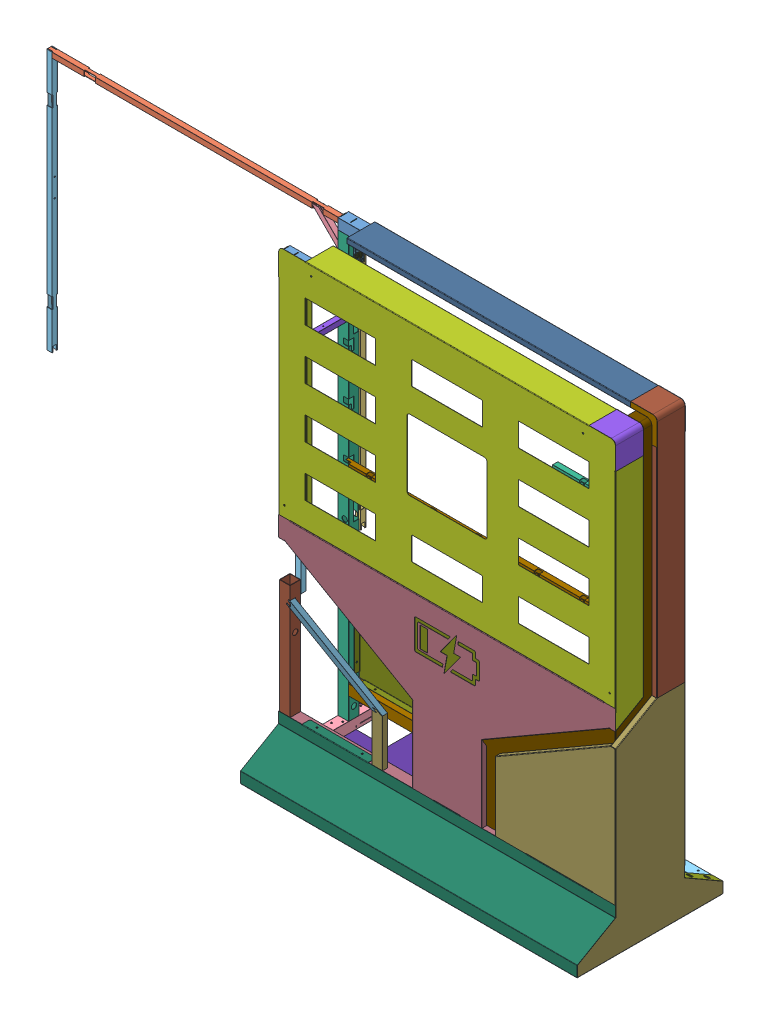
SolidWorks assembly StandV2, configuration Default. Lengths in mm.
Overall size (2398.62 1730.34 547.63).
95 component instances, 56 part files, 48 mates.
Components (placement in the parent):
- Chassis^StandV2-1: Chassis^StandV2 [Default] at (0 0 963.5395) size (2397 1715.34 546.5) (virtual)
  - caster wheel.step-1: caster wheel.step [Default] at (-58.45 -50.6 58.45) x (0 0 1) z (-1 0 0) size (94.94 69.87 60)
  - wheel mount-1: wheel mount [Default] at (5 1.5 -5) x (0 0 1) z (0 -1 0) size (125 125 2)
  - side wheel support-1: side wheel support [Default] at (-104 -13.5 2) size (116.65 17 2)
  - side wheel support-2: side wheel support [Default] at (0 -13.5 104) x (0 0 -1) z (1 0 0) size (116.65 17 2)
  - Bottom depth-1: Bottom depth [Default] at (1065 -10.5 -391.5) size (40 40 546.5)
  - Bottom width-1: Bottom width [Default] at (1085 -10.5 -391.5) x (-1 0 0) z (0 0 -1) size (1220 40 40)
  - Bottom width-2: Bottom width [Default] at (-135 -10.5 155) size (1220 40 40)
  - Bottom depth-2: Bottom depth [Default] at (-115 -10.5 155) x (-1 0 0) z (0 0 -1) size (40 40 546.5)
  - Height main hinge-1: Height main hinge [Default] at (-155 1647 -208.2) x (0 0 -1) z (-1 0 0) size (40 1637.5 40)
  - Skewed depth-1: Skewed depth [Default] at (-115 -5.141 135) x (-1 0 0) z (0 0.5 -0.866025) size (40 40 165.35)
  - Skewed depth-2: Skewed depth [Default] at (1065 -5.141 -371.5) x (1 0 0) z (0 0.5 0.866025) size (40 40 165.35)
  - Skewed depth right-1: Skewed depth right [Default] at (1105 -5.141 135) x (-1 0 0) z (0 0.5 -0.866025) size (40 40 165.35)
  - Skewed depth right-2: Skewed depth right [Default] at (-155 -5.141 -371.5) x (1 0 0) z (0 0.5 0.866025) size (40 40 165.35)
  - Width main thick bottom-1: Width main thick bottom [Default] at (1085 152 -208.2) x (0 0 -1) z (0 1 0) size (40 1220 40)
  - Height main lock-1: Height main lock [Default] at (1105 1647 -208.2) x (-1 0 0) z (0 0 1) size (40 1637.5 40)
  - Height main thick front bottom-1: Height main thick front bottom [Default] at (-155 580.5 -28.1973) x (1 0 0) z (0 0 -1) size (40 571 40)
  - bottom center down height-1: bottom center down height [Default] at (191.4 132 -8.1973) x (0 0 1) z (-1 0 0) size (20 208 40)
  - Width main thick bottom front-1: Width main thick bottom front [Default] at (1085 112 -28.1973) x (0 0 1) z (0 -1 0) size (40 1220 40)
  - bottom Skewed1-1: bottom Skewed1 [Default] at (231.4 330 -8.1973) x (-0.5 -0.866025 0) z (0 0 -1) size (20 405 20)
  - bottom center height-1: bottom center height [Default] at (381.93 132 -8.1973) x (0 0 1) z (-1 0 0) size (20 334 40)
  - bottom skewed2-1: bottom skewed2 [Default] at (409.1926 450.2776 11.8027) x (0.5 0.866025 0) z (0 0 1) size (20 623 20)
  - center front-1: center front [Default] at (1053.1943 767.7776 -8.1973) x (0 -1 0) z (0 0 -1) size (20 1156.4 20)
  - height main thick front top-1: height main thick front top [Default] at (-155 748 11.8027) size (40 899 40)
  - width main thick-1: width main thick [Default] at (1105 1606 -28.1973) x (0 0 1) z (0 -1 0) size (40 1260 40)
  - bottom center height right-1: bottom center height right [Default] at (528.06 132 -8.1973) x (0 0 1) z (-1 0 0) size (20 334 40)
  - bottom skewed2-2: bottom skewed2 [Default] at (540.7974 450.2776 -8.1973) x (-0.5 0.866025 0) z (0 0 -1) size (20 623 20)
  - height main thick front topR-1: height main thick front topR [Default] at (1065 748 11.8027) size (40 899 40)
  - bottom center down heightR-1: bottom center down heightR [Default] at (758.6 132 11.8027) x (0 0 -1) z (1 0 0) size (20 208 40)
  - bottom Skewed1-2: bottom Skewed1 [Default] at (718.6 330 11.8027) x (0.5 -0.866025 0) z (0 0 1) size (20 405 20)
  - midJoint-1: midJoint [Default] at (-114 534.25 -48.1973) x (-1 0 0) z (0 0 -1) size (20 260 20)
  - midJoint-2: midJoint [Default] at (1064 794.25 -48.1973) x (1 0 0) z (0 0 -1) size (20 260 20)
  - width sub-1: width sub [Default] at (1085 1416 -8.1973) x (0 0 1) z (0 -1 0) size (20 1220 20)
  - Height main thick front bottomR-1: Height main thick front bottomR [Default] at (1065 580.5 -28.1973) x (1 0 0) z (0 0 -1) size (40 571 40)
  - width main thick-2: width main thick [Default] at (1105 1606 -248.2) x (0 0 1) z (0 -1 0) size (40 1260 40)
  - shelf depth-1: shelf depth [Default] at (-50 1416 6.8) x (0 1 0) z (-1 0 0) size (20 230 20)
  - width subR-1: width subR [Default] at (-135 1416 -208.2) x (0 0 -1) z (0 -1 0) size (20 1220 20)
  - height sub-1: height sub [Default] at (285 826 -8.1973) x (-1 0 0) z (0 0 -1) size (20 796.5 20)
  - middle width sub-1: middle width sub [Default] at (1085 1226 -8.1973) x (0 0 1) z (0 -1 0) size (20 435 20)
  - height sub-2: height sub [Default] at (685 826 -8.1973) x (-1 0 0) z (0 0 -1) size (20 796.5 20)
  - middle width subR-1: middle width subR [Default] at (1085 1226 -8.1973) x (0 0 1) z (0 -1 0) size (20 435 20)
  - middle width sub-2: middle width sub [Default] at (1085 1036 -8.1973) x (0 0 1) z (0 -1 0) size (20 435 20)
  - soss hinge-1: soss hinge [Predeterminado] at (-113.0697 1571.1835 -253.2465) x (0.95707 0 0.289857) z (0 1 0) size (37.33 27.29 60) (flexible)
    - User Library-Bisagra oculta-1_Pasador fijo-1: User Library-Bisagra oculta-1_Pasador fijo [Predeterminado] at (-4.6863 1.9141 -59.6835) size (2 2 40)
    - User Library-Bisagra oculta-1_Pasador fijo-2: User Library-Bisagra oculta-1_Pasador fijo [Predeterminado] at (-1.2118 -9.5581 -57.391) x (0.983795 -0.179294 0) z (0 0 -1) size (2 2 40)
    - User Library-Bisagra oculta-1_Cuerpo bisagra oculta-1: User Library-Bisagra oculta-1_Cuerpo bisagra oculta [Predeterminado] at (3.6009 -18.5491 -74.6835) x (0 0 1) z (-0.95707 -0.289857 0) size (60 12 17.45)
    - User Library-Bisagra oculta-1_Cuerpo bisagra oculta-2: User Library-Bisagra oculta-1_Cuerpo bisagra oculta [Predeterminado] at (-5.6707 12.0645 -14.6835) x (0 0 -1) z (-0.95707 -0.289857 0) size (60 12 17.45)
    - User Library-Bisagra oculta-1_Pasador movil-1: User Library-Bisagra oculta-1_Pasador movil [Predeterminado] at (-3.4154 -16.4946 -56.9235) x (-0.585336 0.810791 0) z (0 0 1) size (2 2 24.5)
    - User Library-Bisagra oculta-1_Pasador movil-2: User Library-Bisagra oculta-1_Pasador movil [Predeterminado] at (-10.3682 6.4624 -56.9435) x (-0.603635 0.797261 0) z (0 0 1) size (2 2 24.5)
    - User Library-Bisagra oculta-1_Ensamblaje 4 piezas accinamiento bisagra-2: User Library-Bisagra oculta-1_Ensamblaje 4 piezas accinamiento bisagra [Predeterminado] at (-3.4443 -14.0699 -24.6577) x (-0.39046 0.92062 0) z (0 0 1) size (23.48 13.11 4.52)
      - User Library-Bisagra oculta-1_Pieza accionamiento bisagra-1: User Library-Bisagra oculta-1_Pieza accionamiento bisagra [Predeterminado] at (8.606 -10.3669 -23.4008) size (23.48 13.11 1.14)
      - User Library-Bisagra oculta-1_Pieza accionamiento bisagra-2: User Library-Bisagra oculta-1_Pieza accionamiento bisagra [Predeterminado] at (8.606 -10.3669 -24.5258) size (23.48 13.11 1.14)
      - User Library-Bisagra oculta-1_Pieza accionamiento bisagra-3: User Library-Bisagra oculta-1_Pieza accionamiento bisagra [Predeterminado] at (8.606 -10.3669 -21.1508) size (23.48 13.11 1.14)
      - User Library-Bisagra oculta-1_Pieza accionamiento bisagra-4: User Library-Bisagra oculta-1_Pieza accionamiento bisagra [Predeterminado] at (8.606 -10.3669 -22.2758) size (23.48 13.11 1.14)
    - User Library-Bisagra oculta-1_Ensamblaje 4 piezas accinamiento bisagra-3: User Library-Bisagra oculta-1_Ensamblaje 4 piezas accinamiento bisagra [Predeterminado] at (-3.4443 -14.0699 -15.6577) x (-0.39046 0.92062 0) z (0 0 1) size (23.48 13.11 4.52)
      - User Library-Bisagra oculta-1_Pieza accionamiento bisagra-1: User Library-Bisagra oculta-1_Pieza accionamiento bisagra [Predeterminado] at (8.606 -10.3669 -23.4008) size (23.48 13.11 1.14)
      - User Library-Bisagra oculta-1_Pieza accionamiento bisagra-2: User Library-Bisagra oculta-1_Pieza accionamiento bisagra [Predeterminado] at (8.606 -10.3669 -24.5258) size (23.48 13.11 1.14)
      - User Library-Bisagra oculta-1_Pieza accionamiento bisagra-3: User Library-Bisagra oculta-1_Pieza accionamiento bisagra [Predeterminado] at (8.606 -10.3669 -21.1508) size (23.48 13.11 1.14)
      - User Library-Bisagra oculta-1_Pieza accionamiento bisagra-4: User Library-Bisagra oculta-1_Pieza accionamiento bisagra [Predeterminado] at (8.606 -10.3669 -22.2758) size (23.48 13.11 1.14)
    - User Library-Bisagra oculta-1_Ensamblaje 4 piezas accinamiento bisagra-4: User Library-Bisagra oculta-1_Ensamblaje 4 piezas accinamiento bisagra [Predeterminado] at (-9.0469 4.4291 -73.7092) x (0.185934 -0.982562 0) z (0 0 -1) size (23.48 13.11 4.52)
      - User Library-Bisagra oculta-1_Pieza accionamiento bisagra-1: User Library-Bisagra oculta-1_Pieza accionamiento bisagra [Predeterminado] at (8.606 -10.3669 -23.4008) size (23.48 13.11 1.14)
      - User Library-Bisagra oculta-1_Pieza accionamiento bisagra-2: User Library-Bisagra oculta-1_Pieza accionamiento bisagra [Predeterminado] at (8.606 -10.3669 -24.5258) size (23.48 13.11 1.14)
      - User Library-Bisagra oculta-1_Pieza accionamiento bisagra-3: User Library-Bisagra oculta-1_Pieza accionamiento bisagra [Predeterminado] at (8.606 -10.3669 -21.1508) size (23.48 13.11 1.14)
      - User Library-Bisagra oculta-1_Pieza accionamiento bisagra-4: User Library-Bisagra oculta-1_Pieza accionamiento bisagra [Predeterminado] at (8.606 -10.3669 -22.2758) size (23.48 13.11 1.14)
    - User Library-Bisagra oculta-1_Ensamblaje 4 piezas accinamiento bisagra-5: User Library-Bisagra oculta-1_Ensamblaje 4 piezas accinamiento bisagra [Predeterminado] at (-9.0469 4.4291 -64.7092) x (0.185934 -0.982562 0) z (0 0 -1) size (23.48 13.11 4.52)
      - User Library-Bisagra oculta-1_Pieza accionamiento bisagra-1: User Library-Bisagra oculta-1_Pieza accionamiento bisagra [Predeterminado] at (8.606 -10.3669 -23.4008) size (23.48 13.11 1.14)
      - User Library-Bisagra oculta-1_Pieza accionamiento bisagra-2: User Library-Bisagra oculta-1_Pieza accionamiento bisagra [Predeterminado] at (8.606 -10.3669 -24.5258) size (23.48 13.11 1.14)
      - User Library-Bisagra oculta-1_Pieza accionamiento bisagra-3: User Library-Bisagra oculta-1_Pieza accionamiento bisagra [Predeterminado] at (8.606 -10.3669 -21.1508) size (23.48 13.11 1.14)
      - User Library-Bisagra oculta-1_Pieza accionamiento bisagra-4: User Library-Bisagra oculta-1_Pieza accionamiento bisagra [Predeterminado] at (8.606 -10.3669 -22.2758) size (23.48 13.11 1.14)
    - User Library-Bisagra oculta-1_Pasador central bisagra-1: User Library-Bisagra oculta-1_Pasador central bisagra [Predeterminado] at (2.7394 -2.0992 -35.1835) x (-0.923728 -0.383049 0) z (0 0 -1) size (2.3 2.3 19)
  - width sub-2: width sub [Default] at (1085 846 -8.1973) x (0 0 1) z (0 -1 0) size (20 1220 20)
  - below door height-1: below door height [Default] at (1085 604 -228.2) x (0 1 0) z (0 0 1) size (20 1220 20)
  - hinge holder-1: hinge holder [Default] at (-133.5 1466.5 -226.2) x (0 0 -1) z (1 0 0) size (20 120 20)
  - Door height hinge-1: Door height hinge [Default] at (-1292 1603 -252.6868) x (0 -1 0) z (0 0 1) size (20 1177 20)
  - door width-1: door width [Default] at (-115 628 -252.6868) x (0 0 -1) z (1 0 0) size (20 975 20)
  - door trig-1: door trig [Default] at (-106.9764 1434.9764 -272.6868) x (-0.707107 -0.707107 0) z (0 0 -1) size (20 249.5 20)
  - door width lock-1: door width lock [Default] at (-1292 626 -272.6868) x (0 0 1) z (-1 0 0) size (20 977 20)
  - middle width subR-2: middle width subR [Default] at (1085 1036 -8.1973) x (0 0 1) z (0 -1 0) size (20 435 20)
  - width subR-2: width subR [Default] at (-135 846 -208.2) x (0 0 -1) z (0 -1 0) size (20 1220 20)
  - middle sub backR-1: middle sub backR [Default] at (-135 1226 -208.2) x (0 0 -1) z (0 -1 0) size (20 435 20)
- front top surface-wrapper-1: front top surface-wrapper [Default] at (-156.5 792 976.3422) size (1263 940.7 106)
- edge bigR-1: edge bigR [Default] at (1105.5 1562 975.3422) x (-1 0 0) z (0 0 -1) size (100 100 104)
- edge side-1: edge side [Default] at (1090.5 1646 870.3422) x (-1 0 0) z (0 0 -1) size (100 100 20)
- top surface backside-1: top surface backside [Default] at (-56.5 1633.2326 819.3422) size (1063 56 106)
- side surface backRL-1: side surface backRL [Default] at (1046.8043 1562 819.3422) x (0 0 -1) z (-1 0 0) size (106 914 100)
- side surface bottomRL-1: side surface bottomRL [Default] at (1106.5 153 974.3422) x (0 0 -1) z (1 0 0) size (546.6 760.32 451)
- front bottom surface1-1: front bottom surface1 [Default] at (475 153 976.3422) size (1263 639 31)
- aux bottom wrapper-1: aux bottom wrapper [Default] at (1087.5 737.4865 985.0332) x (0 -0.866025 -0.5) z (0 -0.5 0.866025) size (22 20 118)
- bottom surfaceF-1: bottom surfaceF [Default] at (1106.5 112.83 976.3422) x (0 0 1) z (-1 0 0) size (174.33 164.92 1263.25)
- bottom surfaceB-1: bottom surfaceB [Default] at (-156.5 112.83 714.3422) x (0 0 -1) z (1 0 0) size (174.33 164.95 1263.25) (hidden)
- backBottomSurface-1: backBottomSurface [Default] at (475 389 714.3422) x (0 -1 0) z (0 0 1) size (472 1180 21)
- floor surface-1: floor surface [Default] at (-135 -11.5 1098.2895) x (0 0 -1) z (-1 0 0) size (506 1 1220)
- side long cover-1: side long cover [Default] at (1085.5 628.77 785.3422) x (0 0 1) z (-1 0 0) size (155 1497.93 495.76)
- edge side-2: edge side [Default] at (1090.5 1646 820.3422) x (0 -1 0) z (0 0 1) size (100 100 20)
- edge side back-1: edge side back [Default] at (1090.5 1646 714.3395) x (-1 0 0) z (0 0 -1) size (100 100 15)
Mates (geometry in assembly coordinates):
- Coincident239: coincident anti-aligned: plane of Chassis^StandV2-1/caster wheel.step-1 through (-58.45 0 1021.9895) normal (0 -1 0)
- Coincident240: coincident aligned: plane of Chassis^StandV2-1/side wheel support-2 through (0 -13.5 1067.5395) normal (1 0 0)
- Coincident241: coincident anti-aligned: plane of Chassis^StandV2-1/height main thick front top-1 through (-154.5 1647 975.3422) normal (0 0 1); plane of front top surface-wrapper-1 through (-140.5 1646 975.3422) normal (0 0 -1)
- Distance4: distance = 0.5 mm anti-aligned: plane of front top surface-wrapper-1 through (-155.5 792 976.3422) normal (1 0 0); plane of Chassis^StandV2-1/height main thick front top-1 through (-155 1647 974.8422) normal (-1 0 0)
- Coincident242: coincident: plane of Chassis^StandV2-1/width main thick-1 through (-155 1646 935.8422) normal (0 1 0); line of front top surface-wrapper-1 through (1106.5 1646 975.3422) axis (0 0 1)
- Coincident243: coincident aligned: plane of front top surface-wrapper-1 through (-156.5 1662 976.3422) normal (0 1 0); plane of edge bigR-1 through (1006.5 1662 871.3422) normal (0 1 0)
- Coincident245: coincident anti-aligned: plane of front top surface-wrapper-1 through (-140.5 1646 975.3422) normal (0 0 -1); plane of edge bigR-1 through (1106.5 1646 975.3422) normal (0 0 1)
- Coincident246: coincident anti-aligned: plane of front top surface-wrapper-1 through (1006.5 1662 872.3422) normal (1 0 0); plane of edge bigR-1 through (1006.5 1662 871.3422) normal (-1 0 0)
- Coincident249: coincident aligned: plane of front top surface-wrapper-1 through (-156.5 792 870.3422) normal (0 0 -1); plane of edge side-1 through (1090.5 1646 870.3422) normal (0 0 -1)
- Coincident250: coincident aligned: plane of edge bigR-1 through (1006.5 1662 871.3422) normal (0 1 0); plane of edge side-1 through (1090.5 1662 871.3422) normal (0 1 0)
- Coincident251: coincident anti-aligned: plane of front top surface-wrapper-1 through (1006.5 1644 870.3422) normal (1 0 0); plane of edge side-1 through (1006.5 1662 871.3422) normal (-1 0 0)
- Coincident252: coincident aligned: plane of front top surface-wrapper-1 through (-156.5 1662 976.3422) normal (0 1 0); plane of top surface backside-1 through (1006.5 1662 715.3422) normal (0 1 0)
- Coincident253: coincident aligned: plane of front top surface-wrapper-1 through (-56.5 1662 975.3422) normal (-1 0 0); plane of top surface backside-1 through (-56.5 1660 820.3422) normal (-1 0 0)
- Distance5: distance = 50 mm anti-aligned: plane of front top surface-wrapper-1 through (-156.5 792 870.3422) normal (0 0 -1); plane of top surface backside-1 through (1006.5 1661 820.3422) normal (0 0 1)
- Distance6: distance = 50 mm anti-aligned: plane of front top surface-wrapper-1 through (-156.5 792 870.3422) normal (0 0 -1); plane of side surface backRL-1 through (1105.5 748 820.3422) normal (0 0 1)
- Coincident254: coincident aligned: plane of front top surface-wrapper-1 through (1086.5 1562 889.3422) normal (0 1 0); plane of side surface backRL-1 through (1086.5 1562 818.3422) normal (0 1 0)
- Coincident255: coincident aligned: plane of front top surface-wrapper-1 through (1106.5 792 976.3422) normal (1 0 0); plane of side surface backRL-1 through (1106.5 748 715.3422) normal (1 0 0)
- Coincident256: coincident aligned: plane of side surface backRL-1 through (1106.5 748 715.3422) normal (1 0 0); plane of side surface bottomRL-1 through (1106.5 153 974.3422) normal (1 0 0)
- Coincident257: coincident aligned: plane of side surface backRL-1 through (1065.5 748 714.3422) normal (0 0 -1); plane of side surface bottomRL-1 through (1106.5 153 714.3422) normal (0 0 -1)
- Distance7: distance = 1 mm anti-aligned: plane of front bottom surface1-1 through (475 791 976.3422) normal (0 1 0); plane of front top surface-wrapper-1 through (-156.5 792 976.3422) normal (0 -1 0)
- Coincident258: coincident aligned: plane of front top surface-wrapper-1 through (-140.5 1646 976.3422) normal (0 0 1); plane of front bottom surface1-1 through (475 153 976.3422) normal (0 0 1)
- Coincident259: coincident aligned: plane of front top surface-wrapper-1 through (1106.5 792 976.3422) normal (1 0 0); plane of aux bottom wrapper-1 through (1106.5 718.434 974.0332) normal (1 0 0)
- Coincident260: coincident anti-aligned: plane of front top surface-wrapper-1 through (1105.5 721.4342 970.8368) normal (0 -0.866025 -0.5); plane of aux bottom wrapper-1 through (1087.5 719.3 974.5332) normal (0 0.866025 0.5)
- Coincident262: coincident anti-aligned: line of front top surface-wrapper-1 through (1106.5 778.3 872.3422) axis (-1 0 0); line of aux bottom wrapper-1 through (1088.5 778.3 872.3422) axis (1 0 0)
- Coincident263: coincident aligned: plane of front top surface-wrapper-1 through (1106.5 792 976.3422) normal (1 0 0); plane of front bottom surface1-1 through (1106.5 731.5 975.3422) normal (1 0 0)
- Coincident264: coincident anti-aligned: plane of side surface backRL-1 through (1088.5 748 820.3422) normal (0 -1 0); plane of side surface bottomRL-1 through (1105.5 748 818.8422) normal (0 1 0)
- Coincident271: coincident aligned: plane of side surface bottomRL-1 through (1106.5 153 974.3422) normal (1 0 0); plane of bottom surfaceB-1 through (1106.5 29.7913 572.515) normal (1 0 0)
- Coincident272: coincident aligned: plane of side surface bottomRL-1 through (1106.5 153 974.3422) normal (1 0 0); plane of bottom surfaceF-1 through (1106.5 28.9253 1118.6694) normal (1 0 0)
- Coincident273: coincident anti-aligned: plane of Chassis^StandV2-1/Width main thick bottom front-1 through (-135 112.5 975.3422) normal (0 0 1); plane of bottom surfaceF-1 through (-156.5 153 975.3422) normal (0 0 -1)
- Coincident276: coincident anti-aligned: plane of side surface bottomRL-1 through (1014 153 951.3422) normal (0 -1 0); plane of bottom surfaceF-1 through (1014 153 951.3422) normal (0 1 0)
- Coincident277: coincident anti-aligned: plane of Chassis^StandV2-1/Width main thick bottom-1 through (-135 152 754.8395) normal (0 1 0); plane of bottom surfaceB-1 through (-99 152 739.3422) normal (0 -1 0)
- Coincident278: coincident aligned: plane of side surface bottomRL-1 through (1106.5 153 974.3422) normal (1 0 0); plane of bottom surfaceB-1 through (1106.5 28.9253 573.015) normal (1 0 0)
- Coincident279: coincident aligned: plane of side surface bottomRL-1 through (1106.5 153 714.3422) normal (0 0 -1); plane of bottom surfaceB-1 through (1106.5 153 714.3422) normal (0 0 -1)
- Coincident280: coincident anti-aligned: plane of bottom surfaceB-1 through (-99 153 739.3422) normal (0 1 0); plane of backBottomSurface-1 through (475 153 714.3422) normal (0 -1 0)
- Coincident281: coincident anti-aligned: plane of Chassis^StandV2-1/Height main lock-1 through (1065 9.5 754.8395) normal (-1 0 0); plane of backBottomSurface-1 through (1065 389 714.3422) normal (1 0 0)
- Coincident282: coincident aligned: plane of side surface bottomRL-1 through (1106.5 153 714.3422) normal (0 0 -1); plane of backBottomSurface-1 through (1065 625 714.3422) normal (0 0 -1)
- Coincident283: coincident anti-aligned: plane of Chassis^StandV2-1/Bottom depth-2 through (-115.5 -10.5 572.0395) normal (0 -1 0); plane of floor surface-1 through (-135 -10.5 1098.2895) normal (0 1 0)
- Distance8: distance = 19.75 mm anti-aligned: plane of floor surface-1 through (0 -10.5 1098.2895) normal (0 0 1); plane of Chassis^StandV2-1/Bottom width-2 through (1085 -10 1078.5395) normal (0 0 -1)
- Distance9: distance = 20 mm anti-aligned: plane of floor surface-1 through (-135 -10.5 963.2895) normal (-1 0 0); plane of Chassis^StandV2-1/Bottom depth-2 through (-115 -10 572.0395) normal (1 0 0)
- Coincident286: coincident anti-aligned: plane of front top surface-wrapper-1 through (1086.5 792 976.3422) normal (-1 0 0); plane of side long cover-1 through (1086.5 628.77 785.3422) normal (1 0 0)
- Coincident287: coincident anti-aligned: plane of front top surface-wrapper-1 through (-156.5 1642 976.3422) normal (0 -1 0); plane of side long cover-1 through (1085.5 1642 785.3422) normal (0 1 0)
- Coincident285: coincident aligned: plane of front top surface-wrapper-1 through (1086.5 778.3 889.3422) normal (0 0 1); plane of side long cover-1 through (1086.5 778.41 889.3422) normal (0 0 1)
- Coincident288: coincident aligned: plane of side surface backRL-1 through (1105.5 748 820.3422) normal (0 0 1); plane of edge side-2 through (1090.5 1646 820.3422) normal (0 0 1)
- Coincident290: coincident aligned: plane of side surface backRL-1 through (1046.8043 1662 819.3422) normal (0 1 0); plane of edge side-2 through (1090.5 1662 819.3422) normal (0 1 0)
- Coincident291: coincident aligned: plane of side surface backRL-1 through (1106.5 748 715.3422) normal (1 0 0); plane of edge side-2 through (1106.5 1646 819.3422) normal (1 0 0)
- Coincident292: coincident anti-aligned: plane of Chassis^StandV2-1/width main thick-2 through (-155 1606.5 715.3395) normal (0 0 -1); plane of edge side back-1 through (1090.5 1646 715.3395) normal (0 0 1)
- Coincident293: coincident anti-aligned: plane of top surface backside-1 through (1006.5 1644 818.3422) normal (1 0 0); plane of edge side back-1 through (1006.5 1662 715.3395) normal (-1 0 0)
- Coincident294: coincident aligned: plane of side surface backRL-1 through (1046.8043 1662 819.3422) normal (0 1 0); plane of edge side back-1 through (1090.5 1662 715.3395) normal (0 1 0)
